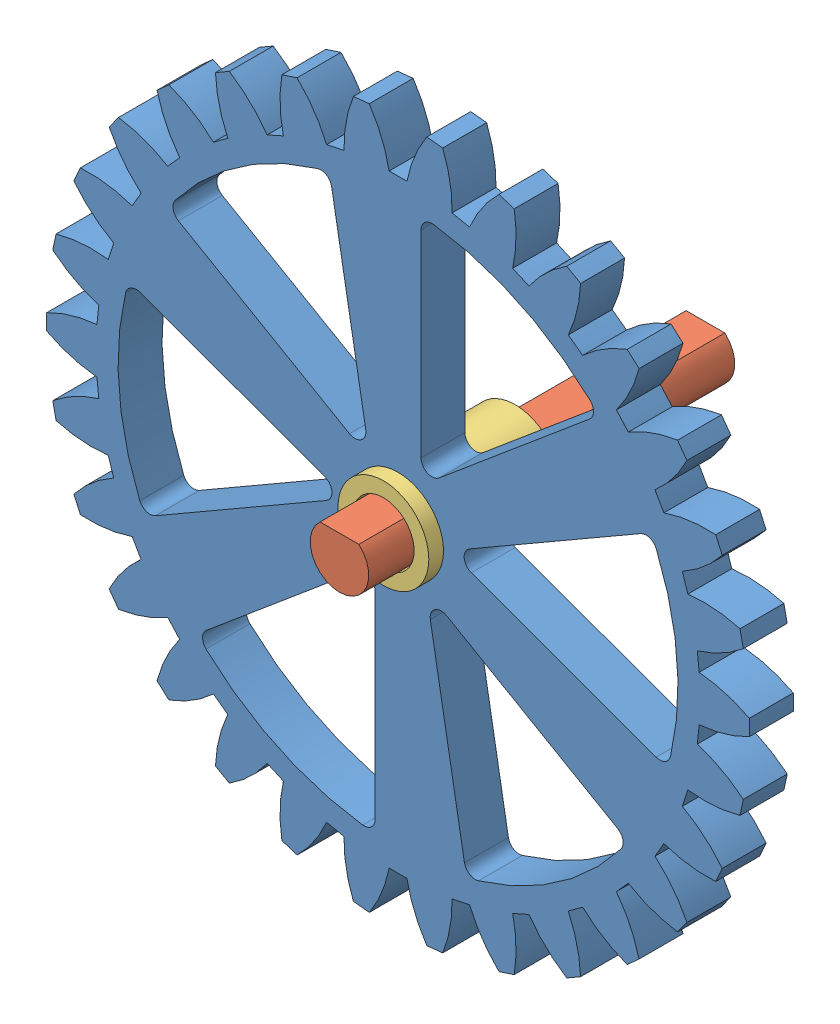
SolidWorks assembly sub 3, configuration Default. Lengths in mm.
Overall size (48 47.84 25).
4 component instances, 3 part files, 6 mates.
Components (placement in the parent):
- root_gear-1: root_gear [30T 1.5Mod] at (17.5723 27.0157 34.1899) size (48 47.84 3)
- axle-1: axle [25 mm Tall] at (17.5723 27.0157 16.1899) size (4 3.5 25)
- spacer-1: spacer [5 mm Tall] at (17.5723 27.0157 29.1899) size (6.2 6.2 5)
- spacer-2: spacer [1 mm Tall] at (17.5723 27.0157 37.1899) size (6.2 6.2 1)
Mates (geometry in assembly coordinates):
- Concentric1: concentric aligned: cylinder of axle-1 through (17.5723 27.0157 41.1899) axis (0 0 -1) radius 2; cylinder of spacer-1 through (17.5723 27.0157 34.1899) axis (0 0 -1) radius 2.1
- Concentric2: concentric aligned: cylinder of axle-1 through (17.5723 27.0157 41.1899) axis (0 0 -1) radius 2; cylinder of spacer-2 through (17.5723 27.0157 38.1899) axis (0 0 -1) radius 2.1
- Coincident1: coincident anti-aligned: plane of root_gear-1 through (17.5723 27.0157 37.1899) normal (0 0 1); plane of spacer-2 through (17.5723 27.0157 37.1899) normal (0 0 -1)
- Coincident2: coincident anti-aligned: plane of root_gear-1 through (17.5723 27.0157 34.1899) normal (0 0 -1); plane of spacer-1 through (17.5723 27.0157 34.1899) normal (0 0 1)
- Concentric3: concentric anti-aligned: cylinder of root_gear-1 through (17.5723 27.0157 34.1899) axis (0 0 1) radius 2; cylinder of axle-1 through (17.5723 27.0157 41.1899) axis (0 0 -1) radius 2
- Distance1: distance = 3 mm aligned: plane of spacer-2 through (17.5723 27.0157 38.1899) normal (0 0 1); plane of axle-1 through (17.5723 27.0157 41.1899) normal (0 0 1)
